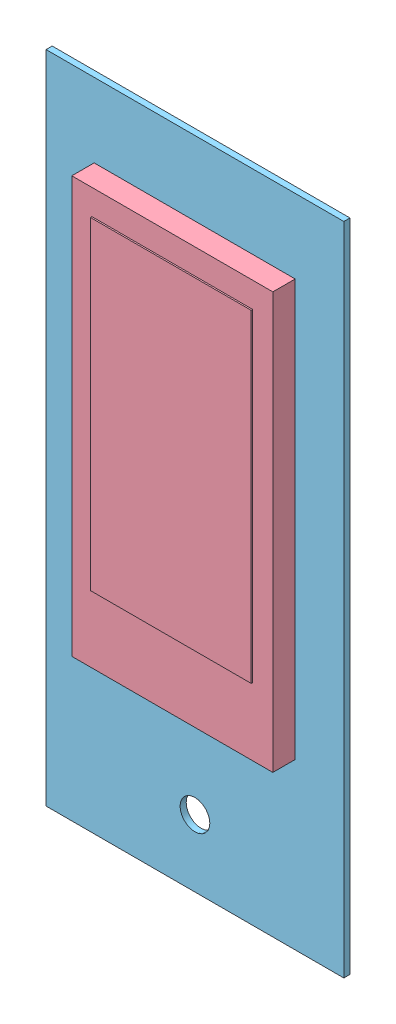
SolidWorks assembly Screen_st7735, configuration 默认. Lengths in mm.
Overall size (20 44 4.09).
16 component instances, 5 part files, 0 mates.
Components (placement in the parent):
- Screen_st7735.step-1: Screen_st7735.step [默认] at origin size (20 44 4.09)
  - R3.step-1: R3.step [默认] at origin size (1 0.5 0.38)
    - RESC1005(0402).step-1: RESC1005(0402).step [默认] at (52.713 120.396 -0.4115) x (-1 0 0) z (0 -1 0) size (1 0.38 0.5)
  - R2.step-1: R2.step [默认] at origin size (1 0.5 0.38)
    - RESC1005(0402).step-1: RESC1005(0402).step [默认] at (50.411 118.872 -0.4115) x (1 0 0) z (0 1 0) size (1 0.38 0.5)
  - Q1.step-1: Q1.step [默认] at origin size (1.4 3 1.14)
    - 1255892816.step-1: 1255892816.step [默认] at (49.276 121.412 -1.5515) size (1.4 3 1.14)
      - Extruded.step-1: Extruded.step [默认] at origin size (1.4 3 1.14)
  - CON2.step-1: CON2.step [默认] at origin size (5.34 9.5 2.1)
    - fpc.step-1: fpc.step [默认] at (50.038 107.569 -0.4369) x (1 0 0) z (0 0 -1) size (5.34 9.5 2.1)
      - ffc_fpc_affc20-16-050-shb-t_(2).step-1: ffc_fpc_affc20-16-050-shb-t_(2).step [默认] at (1.875 2 0) x (0 1 0) z (1 0 0) size (9.5 2.1 5.34)
  - CON1.step-1: CON1.step [默认] at origin size (13.5 27.95 1.6)
    - LCD_ST7735.step-1: LCD_ST7735.step [默认] at (39.605 104.003 0) x (0 1 0) z (0 0 1) size (27.95 13.5 1.6)
  - R1.step-1: R1.step [默认] at origin size (0.5 1 0.38)
    - RESC1005(0402).step-1: RESC1005(0402).step [默认] at (52.451 122.039 -0.4115) x (0 1 0) z (-1 0 0) size (1 0.38 0.5)
  - Board.step-1: Board.step [默认] at (0 0 -0.4115) size (20 44 0.41)
